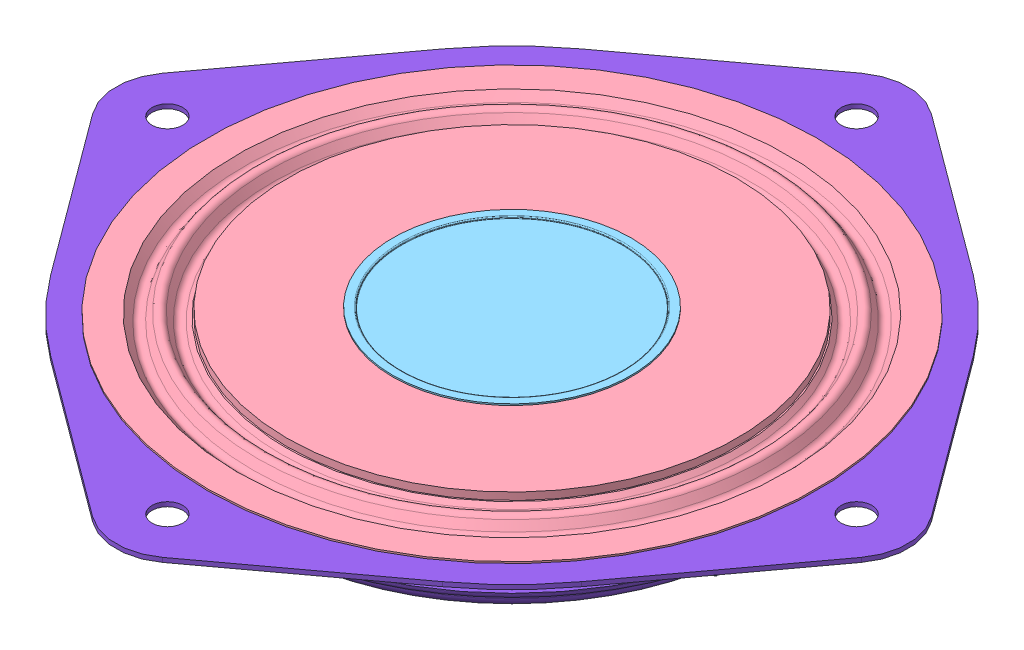
SolidWorks assembly 535B-3.5INCHX8, configuration Default. Lengths in mm.
Overall size (127.28 11.8 127.28).
21 component instances, 17 part files, 106 mates.
Components (placement in the parent):
- 535B-P070-00 U Yoke-1: 535B-P070-00 U Yoke [默认] at (25.1142 0 19.9057) size (37.8 7 37.8)
- 535A-P031-00 Magnet-1: 535A-P031-00 Magnet [默认] at (25.1142 -0.5 19.9057) size (29.9 3.2 29.9)
- 535A-P020-00 Plate-1: 535A-P020-00 Plate [默认] at (25.1142 2.7 19.9057) size (29.95 2.5 29.95) (hidden)
- 535A-P140-00 Spider-1: 535A-P140-00 Spider [默认] at (25.1142 3.4159 19.9057) x (1 0 0.000248) z (-0.000248 0 1) size (72.6 1.6 72.6)
- 535A-P110-00 Cone Paper-1: 535A-P110-00 Cone Paper [默认] at (25.1142 4.0093 19.9057) x (1 0 -0.000631) z (0.000631 0 1) size (83 2.02 83)
- 535A-P150-00 Dust Cap-1: 535A-P150-00 Dust Cap [默认] at (25.1142 4.0093 19.9057) size (32.5 0.4 32.5)
- 535B-P120-00 Voice Coil-2: 535B-P120-00 Voice Coil [默认] at (25.1142 7.7993 19.9057) size (32.21 6.7 32.21)
- 535B-P480-00 Voice coil tube-1: 535B-P480-00 Voice coil tube [默认] at (25.1142 2.1993 19.9057) size (51.9 6.4 51.9)
- 535B-P010-00 basket-2: 535B-P010-00 basket [默认] at (25.1142 3.5793 19.9057) x (0.707107 0 -0.707107) z (0.707107 0 0.707107) size (90 10.75 90)
- 535B-J002-00 Assembling fixture-1: 535B-J002-00 Assembling fixture [Default] at (25.1142 -6.569 19.9057) x (0.999847 0 -0.017517) z (0.017517 0 0.999847) size (72 16.3 72) (hidden)
- 535B-J001-01 Voice jig-1: 535B-J001-01 Voice jig [默认] at (25.1142 4.5077 19.9057) size (30.77 23.92 30.8) (hidden)
- 535B-P090-00 Terminal Assy 正-1: 535B-P090-00 Terminal Assy 正 [默认] at (61.4276 -13.5339 19.9057) x (0 0 -1) z (0.995642 -0.093263 0) size (20.26 5 4.4)
  - Terminal board-1: Terminal board [默认] at origin size (17 5 1)
  - 535B-P090-00 金具-1: 535B-P090-00 金具 [Default] at (-7.7617 16.9627 1) size (7.8 3.5 4.4)
- 535B-P091-00 Terminal Assy 负-1: 535B-P091-00 Terminal Assy 负 [默认] at (-14.6851 23.6816 19.9057) x (0 0 1) z (-0.995642 -0.093263 0) size (20.25 5 4.4)
  - Terminal board-1: Terminal board [默认] x (-1 0 0) z (0 0 1) size (17 5 1)
  - 535B-P090-00 金具-1: 535B-P090-00 金具 [Default] at (-7.75 -20.4729 1) size (7.8 3.5 4.4)
- 535A-P161-00 Gasket-1: 535A-P161-00 Gasket [默认] at (25.1142 3.9793 19.9057) x (0.707107 0 -0.707107) z (0.707107 0 0.707107) size (90 10.64 90) (hidden)
- 535B-J007-00 U Yoke basket  jig-3D-20231208-1: 535B-J007-00 U Yoke basket  jig-3D-20231208 [默认] at (25.1142 11.9793 19.9057) x (-1 0 0) z (0 0 1) size (98 9.7 98) (hidden)
- 535B-J012-00 KLIPPEL测试上模-1: 535B-J012-00 KLIPPEL测试上模 [默认] at (25.1142 -6.6271 19.9057) x (0.994666 0 -0.103149) z (-0.103149 0 -0.994666) size (90.4 41.4 78) (hidden)
- 535B-J002-01 Assembling fixture-1: 535B-J002-01 Assembling fixture [Default] at (25.1142 -6.569 19.9057) x (0.968787 0 -0.247895) z (0.247895 0 0.968787) size (72 22.2 72) (hidden)
Mates (geometry in assembly coordinates):
- 同心1: concentric anti-aligned: cylinder of 535B-P070-00 U Yoke-1 through (25.1142 -1.37 19.9057) axis (0 -1 0) radius 17.2; circle of 535A-P010-00 basket-1
- 重合2: coincident anti-aligned: plane of 535A-P031-00 Magnet-1 through (25.1142 2.7 19.9057) normal (0 1 0); plane of 535A-P020-00 Plate-1 through (25.1142 2.7 19.9057) normal (0 -1 0)
- 同心2: concentric aligned: circle of 353A-P030-00 Magnet-1; circle of 353A-P020-00 Plate-1
- 重合3: coincident anti-aligned: plane of 535B-P070-00 U Yoke-1 through (25.1142 -0.5 19.9057) normal (0 1 0); plane of 535A-P031-00 Magnet-1 through (25.1142 -0.5 19.9057) normal (0 -1 0)
- 同心3: concentric aligned: circle of 535A-P070-00 U Yoke-1; circle of 535A-P030-00 Magnet-1
- 宽度1: width anti-aligned: plane of 353A-P120-00 Voice Coil-1 through (12.825 2.45 0) normal (0 -1 0); plane of 353A-P120-00 Voice Coil-1 through (12.825 5.45 0) normal (0 1 0); plane of 535A-P020-00 Plate-1 through (25.1142 5.2 19.9057) normal (0 1 0); plane of 535A-P020-00 Plate-1 through (25.1142 2.7 19.9057) normal (0 -1 0)
- 同心11: concentric aligned: circle of 535A-P070-00 U Yoke-1; cylinder of 535B-P120-00 Voice Coil-1 through (-1.3513 1.6993 0) axis (0 1 0) radius 15.25
- 同心12: concentric anti-aligned: cylinder of 535B-P070-00 U Yoke-1 through (25.1142 0 19.9057) axis (0 -1 0) radius 16.4; circle of 535A-P110-00 Cone Paper-1
- 重合11: coincident anti-aligned: plane of 535A-P110-00 Cone Paper-1 through (25.1142 9.5993 19.9057) normal (0 1 0); plane of 535A-P150-00 Dust Cap-1 through (41.1142 9.5993 19.9057) normal (0 -1 0)
- 同心13: concentric anti-aligned: circle of 353A-P110-00 Cone Paper-1; circle of 353A-P150-00 Dust Cap-1
- 重合12: coincident anti-aligned: plane of 535A-P110-00 Cone Paper-1 through (25.1142 8.5993 19.9057) normal (0 -1 0); plane of 535B-P480-00 Voice coil tube-1 through (25.1142 8.5993 19.9057) normal (0 1 0)
- 同心14: concentric anti-aligned: circle of 535A-P110-00 Cone Paper-1; circle of 535B-P480-00 Voice coil tube-1
- 重合13: coincident anti-aligned: plane of 535B-P120-00 Voice Coil-1 through (-1.3513 9.5993 0) normal (0 1 0); plane of 535A-P150-00 Dust Cap-1 through (41.1142 9.5993 19.9057) normal (0 -1 0)
- 重合14: coincident aligned: plane of 535B-P010-00 basket-1 through (0 -12.619 0) normal (1 0 0)
- 同心17: concentric aligned: circle of 535A-P110-00 Cone Paper-1; circle of 535A-P010-00 basket 3D-1.0-1
- 重合20: coincident aligned: plane of 535A-P010-00 basket 3D-1.0-1 through (0 2.0493 0) normal (0 0 1)
- 重合23: coincident anti-aligned: plane of 535A-P110-00 Cone Paper-1 through (62.6142 9.0093 19.882) normal (0 1 0); plane of Test jig-1 through (45.0209 7.8093 -9.4401) normal (0 -1 0)
- 同心19: concentric aligned: circle of 535A-P110-00 Cone Paper-1; circle of Test jig-1
- 同心20: concentric aligned: cylinder of 535B-P070-00 U Yoke-1 through (25.1142 0 19.9057) axis (0 -1 0) radius 16.4; cylinder of 535A-J004-00 Magnet Plate jig-1 through (0 -0.6206 0) axis (0 -1 0) radius 14.99
- 重合24: coincident anti-aligned: plane of 535B-P070-00 U Yoke-1 through (25.1142 -0.5 19.9057) normal (0 1 0); plane of 535A-J004-00 Magnet Plate jig-1 through (16.385 -0.6206 0) normal (0 -1 0)
- 同心21: concentric aligned: cylinder of 535B-P070-00 U Yoke-1 through (25.1142 0 19.9057) axis (0 -1 0) radius 16.4; cylinder of 535B-P480-00 Voice coil tube-1 through (25.1142 8.5993 19.9057) axis (0 -1 0) radius 25.25
- 重合25: coincident anti-aligned: plane of 535A-P110-00 Cone Paper-1 through (25.1142 8.5993 19.9057) normal (0 -1 0); plane of 535B-P480-00 Voice coil tube-1 through (25.1142 8.5993 19.9057) normal (0 1 0)
- 同心22: concentric aligned: circle of 535A-P110-00 Cone Paper-1; circle of 535A-P010-00 basket -3D-1
- 同心23: concentric aligned: cylinder of 535B-P480-00 Voice coil tube-1 through (25.1142 8.5993 19.9057) axis (0 -1 0) radius 25.25; cylinder of VN-1 through (0 0.4106 0) axis (0 -1 0) radius 8
- 重合27: coincident anti-aligned: plane of 535B-P480-00 Voice coil tube-1 through (25.1142 8.5993 19.9057) normal (0 1 0); plane of VN-1 through (26.5 7.2787 0) normal (0 -1 0)
- 同心24: concentric anti-aligned: cylinder of 535B-P120-00 Voice Coil-1 through (-1.3513 1.6993 0) axis (0 1 0) radius 15.25; cylinder of 535A-J001-00 Voice jig-1 through (0 3.3871 0) axis (0 -1 0) radius 15.23
- 重合28: coincident anti-aligned: plane of 535B-P120-00 Voice Coil-1 through (-1.3513 9.5993 0) normal (0 1 0); plane of 535A-J001-00 Voice jig-1 through (15.23 8.2787 0) normal (0 -1 0)
- 同心25: concentric aligned: cylinder of 535A-J001-00 Voice jig-1 through (0 3.3871 0) axis (0 -1 0) radius 14.99; cylinder of 535A-J003-00 Assembling fixture-3D-1 through (0 -6.4562 0) axis (0 -1 0) radius 8
- 重合30: coincident anti-aligned: plane of 535A-J001-00 Voice jig-1 through (14.99 5.0787 0) normal (0 -1 0); plane of 535A-J003-00 Assembling fixture-3D-1 through (15 5.0787 0) normal (0 1 0)
- 重合32: coincident anti-aligned: plane of 535B-P070-00 U Yoke-1 through (25.1142 -2 19.9057) normal (0 -1 0); plane of 535A-J006-00 U Yoke jig-1 through (18.95 -2.1206 0) normal (0 1 0)
- 同心26: concentric aligned: cylinder of 535B-P070-00 U Yoke-1 through (25.1142 0 19.9057) axis (0 -1 0) radius 18.9; circle of 535A-J006-00 U Yoke jig-1
- 宽度7: width aligned: plane of 535B-P010-00 basket-1 through (63.6396 -12.119 -1.05) normal (0 0 1); plane of 535B-P010-00 basket-1 through (63.6396 -12.119 1.05) normal (0 0 -1); plane of 535A-P090-00Terminal Assy 正 - 副本-1/Terminal board-1 through (36.742 3.0755 -1) normal (0 0 1); plane of 535A-P090-00Terminal Assy 正 - 副本-1/Terminal board-1 through (36.742 3.0755 1) normal (0 0 -1)
- 相切6: tangent anti-aligned: cone of 535B-P010-00 basket-1 through (0 -13.6322 0) axis (0 -1 0); plane of 535A-P090-00Terminal Assy 正 - 副本-1/Terminal board-1 through (37.9381 3.9583 -6) normal (-0.994806 0.101786 0)
- 角度1: planar angle = 2.617994 rad aligned: plane of 535B-P070-00 U Yoke-1 through (25.1142 0 19.9057) normal (0 0 1); plane of 535B-P010-00 basket-1 through (0 -12.619 0) normal (0.707107 0 -0.707107)
- 重合37: coincident aligned: plane of 535B-P070-00 U Yoke-1 through (25.1142 0 19.9057) normal (0 0 1); plane of 535B-P480-00 Voice coil tube-1 through (25.1142 2.1993 19.9057) normal (0 0 1)
- 重合38: coincident anti-aligned: plane of 535B-P070-00 U Yoke-1 through (25.1142 -1.37 19.9057) normal (0 -1 0); plane of 535A-P010-00 basket -3D20230103-1 through (0 -1.4906 0) normal (0 1 0)
- 同心27: concentric anti-aligned: circle of 535A-P070-00 U Yoke-1; circle of 535A-P140-00 Spider-1
- 重合41: coincident aligned: plane of 535A-P110-00 Cone Paper-1 through (25.1142 9.5993 19.9057) normal (0 1 0); plane of 535B-P120-00 Voice Coil-2 through (25.1142 9.5993 19.9057) normal (0 1 0)
- 同心28: concentric anti-aligned: circle of 535A-P020-00 Plate-1; circle of 535A-P121-00 Voice Coil-1
- 重合43: coincident anti-aligned: plane of 535B-P070-00 U Yoke-1 through (25.1142 -1.37 19.9057) normal (0 -1 0); plane of 535B-P010-00 basket-1 through (-15.4433 -17.5682 15.4433) normal (0 1 0)
- 同心29: concentric aligned: cylinder of 535B-P480-00 Voice coil tube-1 through (25.1142 7.2493 19.9057) axis (0 -1 0) radius 25.41; circle of Spider jig-1
- 距离1: distance = 0.8 mm anti-aligned: plane of Spider jig-1 through (36.75 2.6294 0) normal (0 -1 0); plane of 535A-P140-00 Spider-1 through (-9.1357 2.55 19.8972) normal (0 1 0)
- 重合48: coincident anti-aligned: plane of 535A-P140-00 Spider-1 through (-9.1357 2.35 19.8972) normal (0 -1 0); plane of 535A-P010-00 basket -3D20230103-1 through (-34.2241 1.6294 0) normal (0 1 0)
- 重合51: coincident anti-aligned: plane of 535B-P010-00 basket-1 through (0 -7.419 -46) normal (0 1 0); plane of 535A-P110-00 Cone Paper-1 through (62.6142 8.7793 19.882) normal (0 -1 0)
- 重合53: coincident anti-aligned: plane of 535A-P110-00 Cone Paper-1 through (25.1142 8.5993 19.9057) normal (0 -1 0); plane of 535B-P480-00 Voice coil tube-1 through (25.1142 8.5993 19.9057) normal (0 1 0)
- 同心30: concentric anti-aligned: circle of 535A-P110-00 Cone Paper-1; cylinder of 535B-P480-00 Voice coil tube-1 through (25.1142 8.5993 19.9057) axis (0 -1 0) radius 25.25
- 重合54: coincident anti-aligned: plane of 535B-P070-00 U Yoke-1 through (25.1142 -1.37 19.9057) normal (0 -1 0); plane of 535A-P010-00 basket-1 through (-21.8402 -17.5682 0) normal (0 1 0)
- 同心31: concentric aligned: circle of 535B-P070-00 U Yoke-1; circle of 535A-P010-00 basket-1
- 重合55: coincident anti-aligned: plane of 535A-P010-00 basket-1 through (-34.2241 -14.4482 0) normal (0 1 0); plane of 535B-P170-00 Paper Gasket-1 through (0 -14.4482 0) normal (0 -1 0)
- 同心32: concentric aligned: circle of 535A-P010-00 basket-1; circle of 535B-P170-Paper Gasket-1
- 重合56: coincident anti-aligned: plane of 535A-P010-00 basket-1 through (32.5269 -8.619 -32.5269) normal (0 1 0); plane of 535B-P171-00 Paper Gasket-1 through (0 -8.619 0) normal (0 -1 0)
- 同心34: concentric aligned: circle of 535A-P110-00 Cone Paper-1; circle of 535B-P171-Paper Gasket-1
- 重合57: coincident anti-aligned: plane of 535A-P110-00 Cone Paper-1 through (25.1142 8.5993 19.9057) normal (0 -1 0); plane of 535B-J002-00 Assembling fixture-3D-1 through (25.125 -7.5989 0) normal (0 1 0)
- 同心35: concentric anti-aligned: cylinder of 535B-P120-00 Voice Coil-2 through (25.1142 1.4993 19.9057) axis (0 1 0) radius 15.25; cylinder of 535B-J002-00 Assembling fixture-3D-1 through (0 -22.7672 0) axis (0 -1 0) radius 8
- 重合58: coincident anti-aligned: plane of 535B-J002-00 Assembling fixture-3D-1 through (14.925 -10.3989 0) normal (0 1 0); plane of 535B-J001-01 Voice jig-1 through (40.1042 6.1993 19.9057) normal (0 -1 0)
- 同心36: concentric aligned: cylinder of 535B-J002-00 Assembling fixture-3D-1 through (0 -22.7672 0) axis (0 -1 0) radius 8; cylinder of 535B-J001-01 Voice jig-1 through (25.1142 4.5077 19.9057) axis (0 -1 0) radius 14.99
- 宽度8: width anti-aligned: plane of 535B-P010-00 basket-2 through (88.7538 3.8793 20.9557) normal (0 0 -1); plane of 535B-P010-00 basket-2 through (88.7538 3.8793 18.8557) normal (0 0 1); plane of 535A-P090-00Terminal Assy 正-1/Terminal board-1 through (35.4249 3.7638 -1) normal (0 0 1); plane of 535A-P090-00Terminal Assy 正-1/Terminal board-1 through (35.4249 3.7638 1) normal (0 0 -1)
- 宽度9: width anti-aligned: plane of 535B-P010-00 basket-2 through (-38.5254 3.8793 18.8557) normal (0 0 1); plane of 535B-P010-00 basket-2 through (-38.5254 3.8793 20.9557) normal (0 0 -1); plane of 535A-P091-00Terminal Assy 负-2/Terminal board-1 through (-38.3473 5.7686 1) normal (0 0 -1); plane of 535A-P091-00Terminal Assy 负-2/Terminal board-1 through (-38.3473 5.7686 -1) normal (0 0 1)
- 重合62: coincident anti-aligned: plane of 535B-P070-00 U Yoke-1 through (25.1142 -2 19.9057) normal (0 -1 0); plane of 535B-J006-00 U Yoke jig-3D-1 through (17.6137 -2 0) normal (0 1 0)
- 同心38: concentric aligned: cylinder of 535B-P070-00 U Yoke-1 through (25.1142 0 19.9057) axis (0 -1 0) radius 18.9; cylinder of 535B-J006-00 U Yoke jig-3D-1 through (-1.3513 -8 0) axis (0 -1 0) radius 8
- 同心39: concentric anti-aligned: circle of 535A-P020-00 Plate-1; cylinder of 535B-J004-00 Magnet Plate jig-1 through (-1.3513 0.1 0) axis (0 -1 0) radius 14.99
- 重合63: coincident aligned: plane of 535B-P070-00 U Yoke-1 through (25.1142 0 19.9057) normal (0 1 0)
- 角度2: planar angle = 0 rad: plane of assembly through (0 0 0) normal (0 0 1); plane of assembly; plane of 535B-P070-00 U Yoke-1 through (25.1142 0 19.9057) normal (0 0 1)
- 重合67: coincident anti-aligned: plane of 535B-P070-00 U Yoke-1 through (25.1142 5 19.9057) normal (0 1 0); plane of 535B-J004-00 Magnet Plate jig-1 through (15.0287 5 0) normal (0 -1 0)
- 重合68: coincident anti-aligned: plane of 535B-P070-00 U Yoke-1 through (25.1142 -1.37 19.9057) normal (0 -1 0); plane of 535B-P010-00 basket-2 through (9.6709 -1.37 35.349) normal (0 1 0)
- 同心40: concentric aligned: circle of 535B-P070-00 U Yoke-1; circle of 535B-P010-00 basket-2
- 角度4: planar angle = 0.785398 rad aligned: plane of 535B-P070-00 U Yoke-1 through (25.1142 0 19.9057) normal (0 0 1); plane of 535B-P010-00 basket-2 through (25.1142 3.5793 19.9057) normal (0.707107 0 0.707107)
- 重合70: coincident anti-aligned: plane of 535B-P070-00 U Yoke-1 through (25.1142 5 19.9057) normal (0 1 0); plane of 535B-J007-00 U Yoke basket  jig-3D-1 through (-1.3513 5 0) normal (0 -1 0)
- 同心42: concentric aligned: circle of 535A-P020-00 Plate-1; cylinder of 535B-J007-00 U Yoke basket  jig-3D-1 through (-1.3513 11.7 0) axis (0 1 0) radius 8
- 同心43: concentric aligned: circle of 535B-P010-00 basket-2; circle of 535B-J007-00 U Yoke basket  jig-3D-1
- 重合71: coincident anti-aligned: plane of 535A-P160-00 Gasket-1 through (-1.3513 8.1793 0) normal (0 1 0); plane of 535B-P010-00 basket-2 through (25.1142 8.1793 -26.0943) normal (0 -1 0)
- 同心44: concentric aligned: circle of 535A-P160-00 Gasket-1; circle of 535B-P010-00 basket-2
- 同心45: concentric anti-aligned: circle of 535A-P160-00 Gasket-1; circle of 535B-P010-00 basket-2
- 重合72: coincident anti-aligned: plane of 535B-P480-00 Voice coil tube-1 through (25.1142 2.1993 19.9057) normal (0 -1 0); plane of 535B-J002-00 Assembling fixture-2 through (23.6903 2.1993 6.7099) normal (0 1 0)
- 同心46: concentric aligned: cylinder of 535B-P480-00 Voice coil tube-1 through (25.1142 8.5993 19.9057) axis (0 -1 0) radius 25.25; cylinder of 535B-J002-00 Assembling fixture-2 through (-1.3513 -6.569 0) axis (0 -1 0) radius 8
- 角度5: planar angle = 0.261799 rad: plane of assembly through (0 0 0) normal (0 0 1); plane of assembly; plane of 535B-J002-00 Assembling fixture-2 through (-1.3513 -6.569 0) normal (-0.258819 0 0.965926)
- 同心47: concentric anti-aligned: circle of 535A-P020-00 Plate-1; cylinder of 535B-J002-00 Assembling fixture-1 through (25.1142 -6.569 19.9057) axis (0 -1 0) radius 14.97
- 重合74: coincident anti-aligned: plane of 535B-P070-00 U Yoke-1 through (25.1142 5 19.9057) normal (0 1 0); plane of 535B-J007-00 U Yoke basket  jig-3D-1 through (-1.3513 5 0) normal (0 -1 0)
- 同心48: concentric aligned: circle of 535A-P020-00 Plate-1; circle of 535B-J007-00 U Yoke basket  jig-3D-1
- 距离2: distance = 0.7 mm anti-aligned: plane of 535A-P110-00 Cone Paper-1 through (25.1142 8.5993 19.9057) normal (0 -1 0); plane of 535A-J002-00 Assembling fixture-2 through (23.8887 7.8993 0) normal (0 1 0)
- 同心50: concentric aligned: cylinder of 535B-P480-00 Voice coil tube-1 through (25.1142 8.5993 19.9057) axis (0 -1 0) radius 25.25; cylinder of 535A-J002-00 Assembling fixture-2 through (-1.3513 -6.569 0) axis (0 -1 0) radius 8
- 重合76: coincident anti-aligned: plane of 535B-P120-00 Voice Coil-2 through (25.1142 9.5993 19.9057) normal (0 1 0); plane of 535B-J001-01 Voice jig-1 through (40.3442 9.5993 19.9057) normal (0 -1 0)
- 同心51: concentric anti-aligned: cylinder of 535B-P120-00 Voice Coil-2 through (25.1142 1.4993 19.9057) axis (0 1 0) radius 15.25; cylinder of 535B-J001-01 Voice jig-1 through (25.1142 4.5077 19.9057) axis (0 -1 0) radius 15.23
- 重合77: coincident anti-aligned: plane of 535B-P120-00 Voice Coil-2 through (25.1142 9.5993 19.9057) normal (0 1 0); plane of 535A-J001-00 Voice jig-1 through (24.6105 9.5993 -16.1073) normal (0 -1 0)
- 同心52: concentric anti-aligned: cylinder of 535B-P120-00 Voice Coil-2 through (25.1142 1.4993 19.9057) axis (0 1 0) radius 15.25; cylinder of 535A-J001-00 Voice jig-1 through (-1.3513 4.7077 0) axis (0 -1 0) radius 15.23
- 宽度10: width anti-aligned: plane of 535B-P010-00 basket-2 through (88.7538 3.8793 18.8557) normal (0 0 1); plane of 535B-P010-00 basket-2 through (88.7538 3.8793 20.9557) normal (0 0 -1); plane of 535B-P090-00 Terminal Assy 正-1/Terminal board-1 through (62.1844 4.1957 20.9057) normal (0 0 -1); plane of 535B-P090-00 Terminal Assy 正-1/Terminal board-1 through (62.1844 4.1957 18.9057) normal (0 0 1)
- 相切8: tangent anti-aligned: cone of 535B-P010-00 basket-2 through (25.1142 2.5661 19.9057) axis (0 -1 0); plane of 535B-P090-00 Terminal Assy 正-1/Terminal board-1 through (63.1737 5.1074 13.9057) normal (-0.995642 0.093263 0)
- 同心53: concentric anti-aligned: cylinder of 535B-P070-00 U Yoke-1 through (25.1142 0 19.9057) axis (0 -1 0) radius 18.9; circle of 535A-P020-00 Plate-1
- 同心54: concentric aligned: circle of 535A-P020-00 Plate-1; cylinder of 535B-P120-00 Voice Coil-2 through (25.1142 1.4993 19.9057) axis (0 1 0) radius 15.25
- 重合78: coincident anti-aligned: plane of 535B-J002-00 Assembling fixture-1 through (40.0819 5.1993 19.6434) normal (0 1 0); plane of 535B-J008-00 Cone jig-1 through (11.0564 8.5993 0) normal (0 -1 0)
- 同心55: concentric aligned: cylinder of 535B-J002-00 Assembling fixture-1 through (25.1142 -6.569 19.9057) axis (0 -1 0) radius 8; cylinder of 535B-J008-00 Cone jig-1 through (-2.1336 6.9077 0) axis (0 -1 0) radius 13.19
- 宽度11: width aligned: plane of 535B-P010-00 basket-2 through (-38.5254 3.8793 18.8557) normal (0 0 1); plane of 535B-P010-00 basket-2 through (-38.5254 3.8793 20.9557) normal (0 0 -1); plane of 535B-P091-00 Terminal Assy 负-1/Terminal board-1 through (-12.1362 6.1199 18.9057) normal (0 0 1); plane of 535B-P091-00 Terminal Assy 负-1/Terminal board-1 through (-12.1362 6.1199 20.9057) normal (0 0 -1)
- 相切9: tangent anti-aligned: cone of 535B-P010-00 basket-2 through (25.1142 2.5661 19.9057) axis (0 -1 0); plane of 535B-P091-00 Terminal Assy 负-1/Terminal board-1 through (-12.939 5.0403 13.9057) normal (0.995642 0.093263 0)
- 重合79: coincident anti-aligned: plane of 535B-P480-00 Voice coil tube-1 through (25.1142 2.1993 19.9057) normal (0 -1 0); plane of 535B-J002-00 Assembling fixture-1 through (51.0353 2.1993 19.4515) normal (0 1 0)
- 重合80: coincident anti-aligned: plane of 535B-P010-00 basket-2 through (25.1142 8.1793 -26.0943) normal (0 -1 0); plane of 535A-P161-00 Gasket-1 through (25.1142 8.1793 19.9057) normal (0 1 0)
- 同心56: concentric aligned: circle of 535B-P010-00 basket-2; circle of 535A-P161-00 Gasket-1
- 重合81: coincident aligned: plane of 535B-P010-00 basket-2 through (25.1142 3.5793 19.9057) normal (0.707107 0 0.707107); plane of 535A-P161-00 Gasket-1 through (25.1142 3.9793 19.9057) normal (0.707107 0 0.707107)
- 重合82: coincident anti-aligned: plane of 535B-P010-00 basket-2 through (25.1142 8.7793 -26.0943) normal (0 1 0); plane of 535B-J007-00 U Yoke basket  jig-3D-20231208-1 through (25.1142 8.7793 19.9057) normal (0 -1 0)
- 同心57: concentric aligned: circle of 535B-P010-00 basket-2; cylinder of 535B-J007-00 U Yoke basket  jig-3D-20231208-1 through (72.1142 6.7793 19.9057) axis (0 1 0) radius 2
- 同心58: concentric aligned: circle of 535B-P010-00 basket-2; circle of 535B-J007-00 U Yoke basket  jig-3D-20231208-1
- 同心59: concentric anti-aligned: cone of 535B-P010-00 basket-2 through (25.1142 -0.6386 19.9057) axis (0 -1 0); cylinder of 535B-J012-00 KLIPPEL测试上模-1 through (25.1142 -6.6271 19.9057) axis (0 1 0) radius 34.4
- 重合83: coincident aligned: circle of 535B-P010-00 basket-2; plane of 535B-J012-00 KLIPPEL测试上模-1 through (63.9062 1.75 15.8829) normal (0 1 0)
- 同心60: concentric aligned: cone of 535B-P010-00 basket-2 through (25.1142 -0.6386 19.9057) axis (0 -1 0); cylinder of 535B-J002-01 Assembling fixture-1 through (25.1142 -6.569 19.9057) axis (0 -1 0) radius 36
- 重合85: coincident anti-aligned: plane of 535A-P110-00 Cone Paper-1 through (25.1142 8.5993 19.9057) normal (0 -1 0); plane of 535B-J002-01 Assembling fixture-1 through (49.5519 8.5993 13.6525) normal (0 1 0)
- 重合86: coincident anti-aligned: plane of 535A-P140-00 Spider-1 through (-1.1858 2.2993 19.8992) normal (0 -1 0); plane of 535B-P480-00 Voice coil tube-1 through (50.4637 2.2993 19.9057) normal (0 1 0)
- 重合87: coincident anti-aligned: plane of 535A-P140-00 Spider-1 through (-9.1357 2.35 19.8972) normal (0 -1 0); plane of 535B-P010-00 basket-2 through (0.9123 2.35 44.1076) normal (0 1 0)
